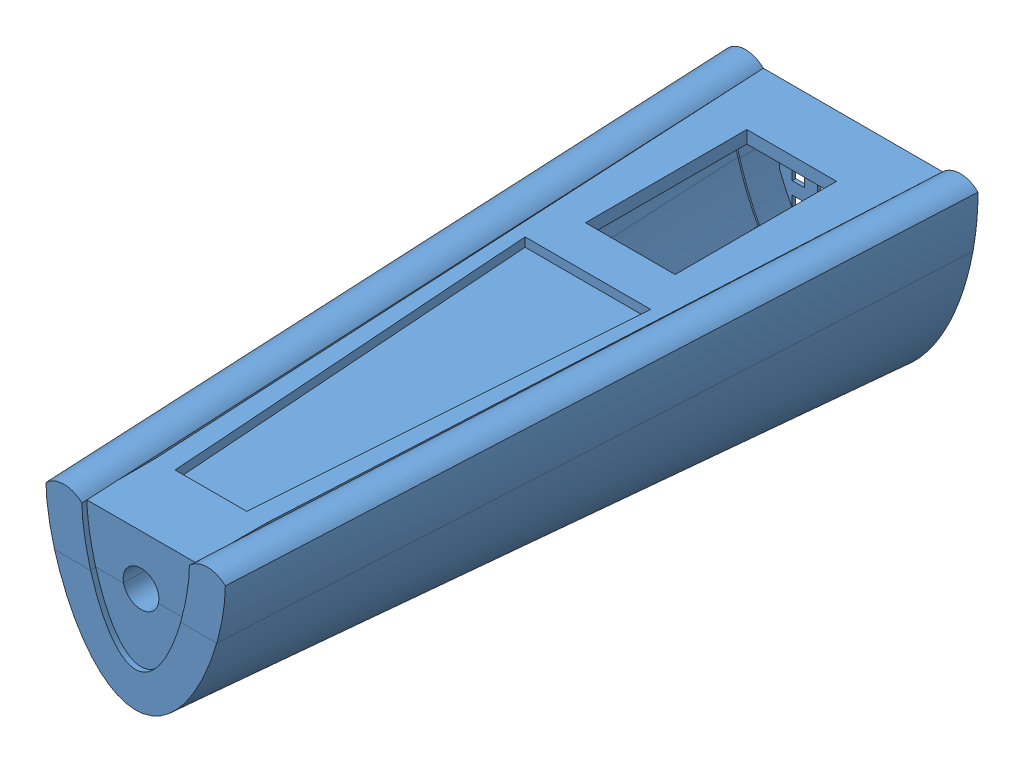
SolidWorks assembly CessnaMicrophone, configuration Default. Lengths in mm.
Overall size (35.4 30.33 101.89).
2 component instances, 2 part files, 4 mates.
Components (placement in the parent):
- Mircophone casing-1: Mircophone casing [Default] at (-4.1505 3.6267 -41.4852) size (35.4 30.33 101.89)
- Part1-1: Part1 [Default] at (-4.1505 3.6267 49.4468)
Mates (geometry in assembly coordinates):
- InPlace1: in place: plane of Mircophone casing-1 through (-4.1505 -17.9525 49.4468) normal (0 0 1); plane of ? through (0 0 49.4468) normal (0 0 1); moOrthogonalPlaneRef_w of Mircophone casing-1 through (-4.1505 -17.9525 49.4468) normal (0 0 1); plane of ? through (0 0 49.4468) normal (0 1 0); plane of Mircophone casing-1 through (-4.1505 -17.9525 49.4468) normal (0 0 1); plane of ? through (0 0 49.4468) normal (1 0 0); plane of Mircophone casing-1 through (-4.1505 -17.9525 49.4468) normal (0 0 1); unknown of Part1-1
- Coincident1: coincident aligned: plane of ?; plane of ?
- Coincident2: coincident aligned: moOrthogonalPlaneRef_w of Mircophone casing-1 through (-4.1505 3.6267 49.4468) normal (0 1 0); plane of Part1^Assem1-1 through (-4.1505 3.6267 49.4468) normal (0 1 0)
- Coincident3: coincident anti-aligned: moOrthogonalPlaneRef_w of Mircophone casing-1 through (-4.1505 3.6267 49.4468) normal (-1 0 0); plane of Part1^Assem1-1 through (-4.1505 3.6267 49.4468) normal (1 0 0)
